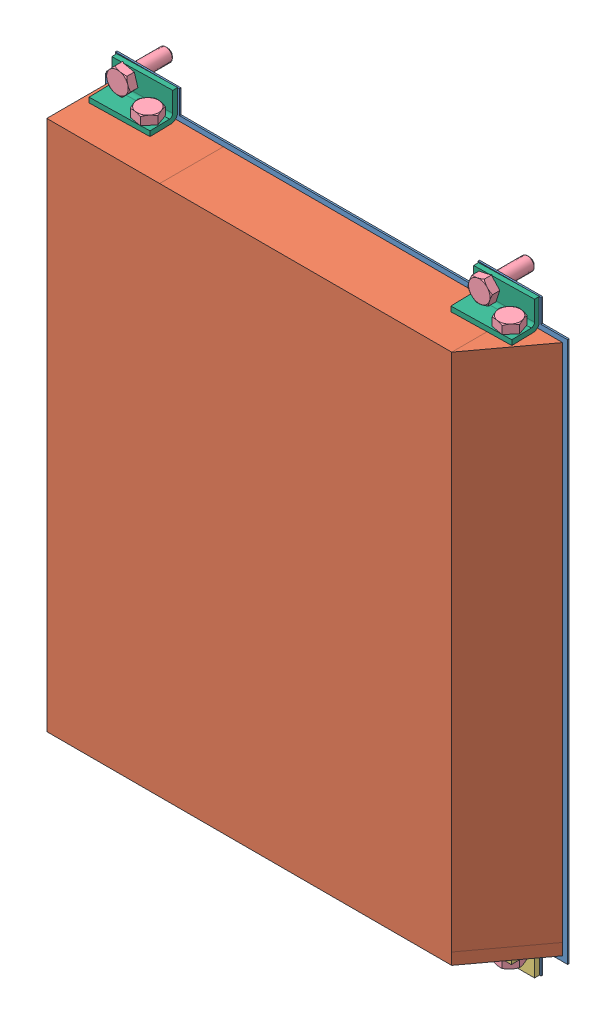
SolidWorks assembly PUTM-G-AM-Assembly, configuration Domyślna. Lengths in mm.
Overall size (284.3 359.87 60.4).
57 component instances, 24 part files, 0 mates.
Components (placement in the parent):
- PUTM-G-AM-LV_Battery-Basket-Assembly(29.10.2019)-1: PUTM-G-AM-LV_Battery-Basket-Assembly(29.10.2019) [Domyślna] at (266.1225 -250.3418 30.9153) x (0.000038 -1 0) z (1 0.000038 0) size (359.86 60.4 284.29)
  - PUTM-H-BT-BB-Cell-1: PUTM-H-BT-BB-Cell [Domyślna] at (-172.986 -113.4847 -217.7798) x (1 0 0) z (0 0 -1) size (74 9.7 186)
  - PUTM-H-BT-BB-Cell-3: PUTM-H-BT-BB-Cell [Domyślna] at (-246.986 -113.4847 -217.7798) x (1 0 0) z (0 0 -1) size (74 9.7 186)
  - PUTM-H-BT-BB-Cell-4: PUTM-H-BT-BB-Cell [Domyślna] at (-330.986 -113.4847 -217.7798) x (1 0 0) z (0 0 -1) size (74 9.7 186)
  - PUTM-H-BT-BB-Cell-5: PUTM-H-BT-BB-Cell [Domyślna] at (-404.986 -113.4847 -217.7798) x (1 0 0) z (0 0 -1) size (74 9.7 186)
  - PUTM-H-BT-BB-Cell-6: PUTM-H-BT-BB-Cell [Domyślna] at (-172.986 -103.7847 -217.7798) x (1 0 0) z (0 0 -1) size (74 9.7 186)
  - PUTM-H-BT-BB-Cell-8: PUTM-H-BT-BB-Cell [Domyślna] at (-404.986 -103.7847 -217.7798) x (1 0 0) z (0 0 -1) size (74 9.7 186)
  - PUTM-H-BT-BB-Cell-9: PUTM-H-BT-BB-Cell [Domyślna] at (-330.986 -103.7847 -217.7798) x (1 0 0) z (0 0 -1) size (74 9.7 186)
  - PUTM-H-BT-BB-Cell-10: PUTM-H-BT-BB-Cell [Domyślna] at (-246.986 -103.7847 -217.7798) x (1 0 0) z (0 0 -1) size (74 9.7 186)
  - PUTM-G-AM-BB-PCB-Connector-v2-1: PUTM-G-AM-BB-PCB-Connector-v2 [Domyślna] at (-311.527 -100.2847 -396.9798) x (-1 0 0) z (0 -1 0) size (60.96 9.2 7.2)
    - 15EDGRC-5.08- 12P-14-00A(H).stp-1: 15EDGRC-5.08- 12P-14-00A(H).stp [Domyślna] at origin size (60.96 9.2 10.6) (hidden)
      - body_1pc.stp-1: body_1pc.stp [Domyślna] at origin size (5.08 9.2 7.2)
      - contact.stp-1: contact.stp [Domyślna] at (0.0085 0 0) size (0.8 6.77 7.1) (hidden)
      - body_1pc_1.stp-1: body_1pc_1.stp [Domyślna] at (-5.08 0 0) size (5.08 9.2 7.2)
      - contact.stp-2: contact.stp [Domyślna] at (-5.0715 0 0) size (0.8 6.77 7.1) (hidden)
      - body_1pc_2.stp-1: body_1pc_2.stp [Domyślna] at (-10.16 0 0) size (5.08 9.2 7.2)
      - contact.stp-3: contact.stp [Domyślna] at (-10.1515 0 0) size (0.8 6.77 7.1) (hidden)
      - body_1pc_3.stp-1: body_1pc_3.stp [Domyślna] at (-15.24 0 0) size (5.08 9.2 7.2)
      - contact.stp-4: contact.stp [Domyślna] at (-15.2315 0 0) size (0.8 6.77 7.1) (hidden)
      - body_1pc_4.stp-1: body_1pc_4.stp [Domyślna] at (-20.32 0 0) size (5.08 9.2 7.2)
      - contact.stp-5: contact.stp [Domyślna] at (-20.3115 0 0) size (0.8 6.77 7.1) (hidden)
      - body_1pc_5.stp-1: body_1pc_5.stp [Domyślna] at (-25.4 0 0) size (5.08 9.2 7.2)
      - contact.stp-6: contact.stp [Domyślna] at (-25.3915 0 0) size (0.8 6.77 7.1) (hidden)
      - body_1pc_6.stp-1: body_1pc_6.stp [Domyślna] at (-30.48 0 0) size (5.08 9.2 7.2)
      - contact.stp-7: contact.stp [Domyślna] at (-30.4715 0 0) size (0.8 6.77 7.1) (hidden)
      - body_1pc_7.stp-1: body_1pc_7.stp [Domyślna] at (-35.56 0 0) size (5.08 9.2 7.2)
      - contact.stp-8: contact.stp [Domyślna] at (-35.5515 0 0) size (0.8 6.77 7.1) (hidden)
      - body_1pc_8.stp-1: body_1pc_8.stp [Domyślna] at (-40.64 0 0) size (5.08 9.2 7.2)
      - contact.stp-9: contact.stp [Domyślna] at (-40.6315 0 0) size (0.8 6.77 7.1) (hidden)
      - body_1pc_9.stp-1: body_1pc_9.stp [Domyślna] at (-45.72 0 0) size (5.08 9.2 7.2)
      - contact.stp-10: contact.stp [Domyślna] at (-45.7115 0 0) size (0.8 6.77 7.1) (hidden)
      - body_1pc_10.stp-1: body_1pc_10.stp [Domyślna] at (-50.8 0 0) size (5.08 9.2 7.2)
      - contact.stp-11: contact.stp [Domyślna] at (-50.7915 0 0) size (0.8 6.77 7.1) (hidden)
      - body_1pc_11.stp-1: body_1pc_11.stp [Domyślna] at (-55.88 0 0) size (5.08 9.2 7.2)
      - contact.stp-12: contact.stp [Domyślna] at (-55.8715 0 0) size (0.8 6.77 7.1) (hidden)
  - PUTM-G-AM-Connector-2: PUTM-G-AM-Connector [Default] at (-141.6452 -111.9847 -461.7418) x (0 0 1) z (1 0 0) size (52.32 25.2 25.2)
  - PUTM-G-AM-BMS-Base-1: PUTM-G-AM-BMS-Base [Domyślna] at (-283.986 -103.7847 -450.7798) size (309 17.9 2)
  - PUTM-G-AM-BMS-1: PUTM-G-AM-BMS [Domyślna] at origin size (40 5.53 31.21)
  - PUTM-G-AM-Case-1: PUTM-G-AM-Case [Domyślna] at (-283.986 -103.7847 -450.7798) x (-1 0 0) z (0 0 -1) size (339 29.4 235) (hidden)
  - PUTM-G-AM-LV-Basket-1: PUTM-G-AM-LV-Basket [Domyślna] at (-250.3519 30.9153 -266.1129) x (0.000038 0 1) z (0 -1 0) size (278.39 354.01 22.4)
  - PUTM-G-AM-LV-Box-1: PUTM-G-AM-LV-Box [Domyślna] at (-250.3519 30.9153 -266.1129) x (0.000038 0 1) z (0 -1 0) size (272.39 320.01 38.4)
  - PUTM-G-AM-LV-Box-Mounting-1: PUTM-G-AM-LV-Box-Mounting [Domyślna] at (-83.4846 -94.0847 -437.2895) x (0 0 1) z (0 -1 0) size (36 17 17)
  - PUTM-G-AM-LV-Box-Mounting-2: PUTM-G-AM-LV-Box-Mounting [Domyślna] at (-83.486 -94.0847 -219.2895) x (0 0 1) z (0 -1 0) size (36 17 17)
  - PUTM-FT-FABORY_DIN933-1: PUTM-FT-FABORY_DIN933 [M8x25 [01210.080.025]] at (-83.686 -104.0847 -209.2895) x (1 0 0) z (0 -0.983634 -0.18018) size (30.3 15.01 13)
  - PUTM-FT-FABORY_DIN933-2: PUTM-FT-FABORY_DIN933 [M8x25 [01210.080.025]] at (-81.986 -102.3847 -229.2895) x (0 -1 0) z (-0.665826 0 -0.746107) size (30.3 15.01 13)
  - PUTM-FT-FABORY_DIN933-3: PUTM-FT-FABORY_DIN933 [M8x25 [01210.080.025]] at (-81.9846 -102.3847 -447.2895) x (0 -1 0) z (-0.286925 0 -0.957953) size (30.3 15.01 13)
  - PUTM-FT-FABORY_DIN933-4: PUTM-FT-FABORY_DIN933 [M8x25 [01210.080.025]] at (-83.6846 -104.0847 -427.2895) x (1 0 0) z (0 -0.984537 -0.17518) size (30.3 15.01 13)
  - PUTM-FT-FABORY_DIN98-1: PUTM-FT-FABORY_DIN98 [M8 [12348.080.001]] at (-98.986 -104.0847 -209.2895) x (0 0.938897 0.344199) z (-1 0 0) size (15.01 13.47 8)
  - PUTM-FT-FABORY_DIN98-2: PUTM-FT-FABORY_DIN98 [M8 [12348.080.001]] at (-98.986 -104.0847 -427.2895) x (0 0.691505 0.722372) z (-1 0 0) size (15.01 13.47 8)
  - PUTM-FT-FABORY_DIN933-5: PUTM-FT-FABORY_DIN933 [M8x25 [01210.080.025]] at (-420.286 -104.0847 -209.2895) x (-1 0 0) z (0 0.983634 0.18018) size (30.3 15.01 13)
  - PUTM-FT-FABORY_DIN933-6: PUTM-FT-FABORY_DIN933 [M8x25 [01210.080.025]] at (-421.986 -102.3847 -229.2895) x (0 -1 0) z (-0.665826 0 0.746107) size (30.3 15.01 13)
  - PUTM-FT-FABORY_DIN933-7: PUTM-FT-FABORY_DIN933 [M8x25 [01210.080.025]] at (-421.9874 -102.3847 -447.2895) x (0 -1 0) z (-0.286925 0 0.957953) size (30.3 15.01 13)
  - PUTM-FT-FABORY_DIN933-8: PUTM-FT-FABORY_DIN933 [M8x25 [01210.080.025]] at (-420.2874 -104.0847 -427.2895) x (-1 0 0) z (0 0.984537 0.17518) size (30.3 15.01 13)
  - PUTM-FT-FABORY_DIN98-3: PUTM-FT-FABORY_DIN98 [M8 [12348.080.001]] at (-404.986 -104.0847 -209.2895) x (0 -0.938897 -0.344199) z (1 0 0) size (15.01 13.47 8)
  - PUTM-FT-FABORY_DIN98-4: PUTM-FT-FABORY_DIN98 [M8 [12348.080.001]] at (-404.986 -104.0847 -427.2895) x (0 -0.691505 -0.722372) z (1 0 0) size (15.01 13.47 8)
  - PUTM-G-AM-LV-Box-Mounting-L-1: PUTM-G-AM-LV-Box-Mounting-L [Domyślna] at (-411.986 -102.7948 -219.3188) x (0 0.020968 0.99978) z (-1 0 0) size (36 17 17)
  - PUTM-G-AM-LV-Box-Mounting-L-2: PUTM-G-AM-LV-Box-Mounting-L [Domyślna] at (-411.9874 -102.7948 -437.3188) x (0 0.020968 0.99978) z (-1 0 0) size (36 17 17)
